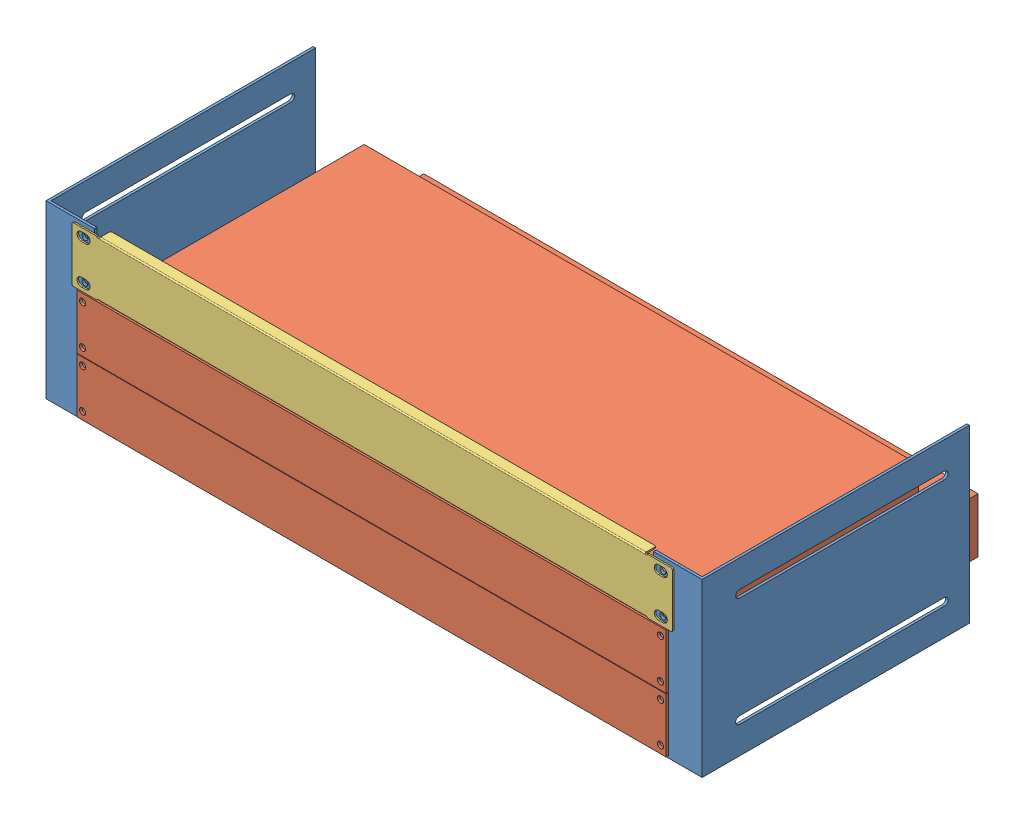
SolidWorks assembly Rack-Audio-Verstärker, configuration Standard. Lengths in mm.
Overall size (528 138 265).
4 component instances, 3 part files, 12 mates.
Components (placement in the parent):
- 3HE-Frame-1: 3HE-Frame [691831GR.3] at (-264 -69 -2) size (528 138 215)
- 1HE-Slice-1: 1HE-Slice [Behringer EPQ304] at (-41 -136.225 -263) size (474 44 265)
- 1HE-Slice-2: 1HE-Slice [Behringer DCX2496] at (-41 -91.775 -215) size (474 44 217)
- Intellinet_712675-1: Intellinet_712675 [Standard] at (-89.5481 -47.5712 0) x (1 0.000022 0) z (0 0 1) size (483 44.5 9)
Mates (geometry in assembly coordinates):
- Deckungsgleich1: coincident anti-aligned: plane of 3HE-Frame-1 through (-264 -69 0) normal (0 0 1); plane of 1HE-Slice-1 through (-41 -136.225 0) normal (0 0 -1)
- Deckungsgleich2: coincident anti-aligned: plane of 3HE-Frame-1 through (-489 -138 0) normal (1 0 0); plane of 1HE-Slice-1 through (-489 -129.5444 -8) normal (-1 0 0)
- Konzentrisch2: concentric anti-aligned: cylinder of 3HE-Frame-1 through (-496.55 -130.105 0) axis (0 0 -1) radius 2.5; cylinder of 1HE-Slice-1 through (-496.55 -130.105 0) axis (0 0 1) radius 2.5
- Deckungsgleich3: coincident aligned: plane of 3HE-Frame-1 through (-264 -69 0) normal (0 0 1); plane of assembly through (0 0 0) normal (0 0 1)
- Deckungsgleich4: coincident aligned: plane of 3HE-Frame-1 through (0 -138 0) normal (1 0 0); plane of assembly through (0 0 0) normal (1 0 0)
- Deckungsgleich5: coincident aligned: plane of 3HE-Frame-1 through (0 0 0) normal (0 1 0); plane of assembly through (0 0 0) normal (0 1 0)
- Deckungsgleich6: coincident anti-aligned: plane of 3HE-Frame-1 through (-264 -69 0) normal (0 0 1); plane of 1HE-Slice-2 through (-41 -91.775 0) normal (0 0 -1)
- Deckungsgleich7: coincident anti-aligned: plane of 3HE-Frame-1 through (-489 -138 0) normal (1 0 0); plane of 1HE-Slice-2 through (-489 -85.0944 -8) normal (-1 0 0)
- Konzentrisch3: concentric anti-aligned: cylinder of 3HE-Frame-1 through (-496.55 -85.655 0) axis (0 0 -1) radius 2.5; cylinder of 1HE-Slice-2 through (-496.55 -85.655 0) axis (0 0 1) radius 2.5
- Deckungsgleich8: coincident anti-aligned: plane of 3HE-Frame-1 through (-264 -69 0) normal (0 0 1); plane of Intellinet_712675-1 through (-264.3003 -25.325 0) normal (0 0 -1)
- Langloch1: slot aligned: cylinder of Intellinet_712675-1 through (-494.7 -41.205 1.2) axis (0 0 -1) radius 3.4; cylinder of 3HE-Frame-1 through (-496.55 -41.205 0) axis (0 0 -1) radius 2.5; cylinder of Intellinet_712675-1 through (-498.4 -41.205 1.2) axis (0 0 -1) radius 3.4
- Langloch2: slot aligned: cylinder of 3HE-Frame-1 through (-31.45 -9.445 0) axis (0 0 -1) radius 2.5; plane of Intellinet_712675-1 through (-30.2006 -12.845 1.2) normal (-0.000022 1 0); cylinder of Intellinet_712675-1 through (-33.9 -9.455 1.2) axis (0 0 -1) radius 3.4
